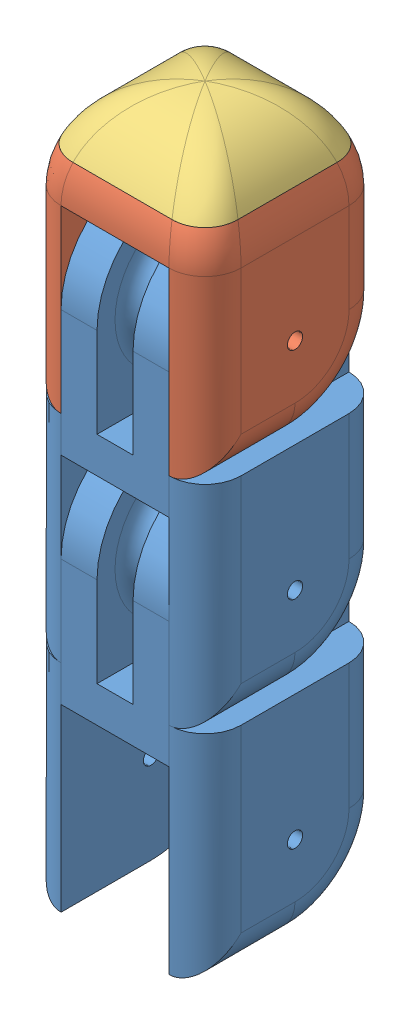
SolidWorks assembly Finger Assembly 5, configuration Default. Lengths in mm.
Overall size (20 78 20).
4 component instances, 3 part files, 9 mates.
Components (placement in the parent):
- Finger Body 5-1: Finger Body 5 [Default] at (8.0779 21.877 43.4324) size (20 44 20)
- Finger Body 5-2: Finger Body 5 [Default] at (8.0779 45.877 43.4324) size (20 44 20)
- Finger Top-1: Finger Top [Default] at (8.0779 69.877 43.4324) size (20 24 20)
- Finger Tip-1: Finger Tip [Default] at (8.0779 69.877 43.4324) size (18.77 6 18.77)
Mates (geometry in assembly coordinates):
- Coincident1: coincident anti-aligned: plane of Finger Body-1 through (14.0779 35.877 53.4324) normal (1 0 0); plane of Finger Body 4-2 through (14.0779 35.877 33.4324) normal (-1 0 0)
- LimitAngle1: limit planar angle = 1.570796 rad aligned: plane of Finger Body-2 through (-1.9221 49.877 53.4324) normal (0 0 1); plane of Finger Body-1 through (8.0779 25.877 43.4324) normal (0 1 0)
- Coincident2: coincident anti-aligned: plane of Finger Body 4-2 through (14.0779 59.877 53.4324) normal (1 0 0); plane of Finger Top-1 through (14.0779 59.877 53.4324) normal (-1 0 0)
- Concentric2: concentric aligned: circle of Finger Body-2; circle of Finger Top-1
- LimitAngle2: limit planar angle = 1.570796 rad anti-aligned: plane of Finger Top-1 through (18.0779 73.877 27.2077) normal (0 1 0); plane of Finger Body-2 through (-1.9221 49.877 53.4324) normal (0 0 1)
- Concentric3: concentric aligned: circle of Finger Body-1; circle of Finger Body-2
- Coincident5: coincident anti-aligned: plane of Finger Top-1 through (18.0779 73.877 27.2077) normal (0 1 0); plane of Finger Tip-1 through (-1.9221 73.877 53.958) normal (0 -1 0)
- Coincident6: coincident anti-aligned: line of Finger Top-1 through (2.5788 73.877 52.5976) axis (1 0 0); line of Finger Tip-1 through (13.577 73.877 52.5976) axis (-1 0 0)
- Coincident7: coincident anti-aligned: line of Finger Top-1 through (-1.0873 73.877 37.9334) axis (0 0 1); line of Finger Tip-1 through (-1.0873 73.877 48.9315) axis (0 0 -1)
